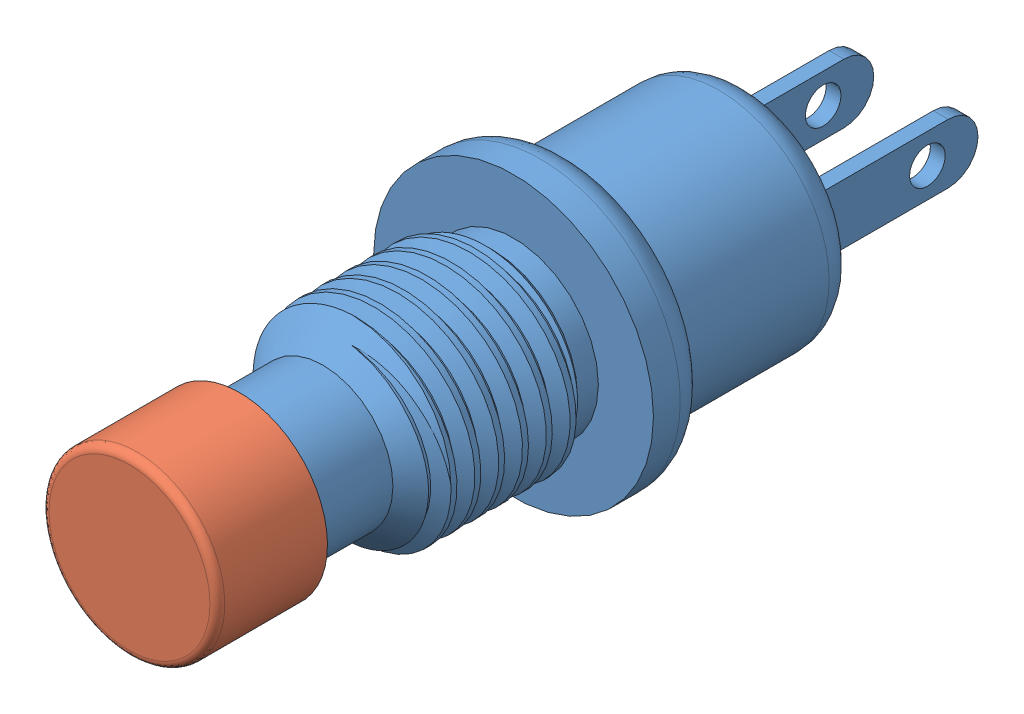
SolidWorks assembly Button Push Body Assembly, configuration Predeterminado. Lengths in mm.
Overall size (9.4 9.4 26.5).
2 component instances, 2 part files, 2 mates.
Components (placement in the parent):
- Button Push Body-1: Button Push Body [Predeterminado] at (-1.6164 0.794 37.9) size (9.4 9.4 22.8)
- Button Push Body Cap-1: Button Push Body Cap [Predeterminado] at (-1.6164 0.794 37.9) x (0.564495 -0.825437 0) z (0 0 1) size (5.9 5.9 3.7)
Mates (geometry in assembly coordinates):
- Concentric1: concentric anti-aligned: circle of Button Push Body-1; circle of Button Push Body Cap-1
- LimitDistance1: limit distance = 0 mm anti-aligned: plane of Button Push Body Cap-1 through (-1.6164 0.794 34.2) normal (0 0 -1); plane of Button Push Body-1 through (-1.6164 0.794 34.2) normal (0 0 1)
